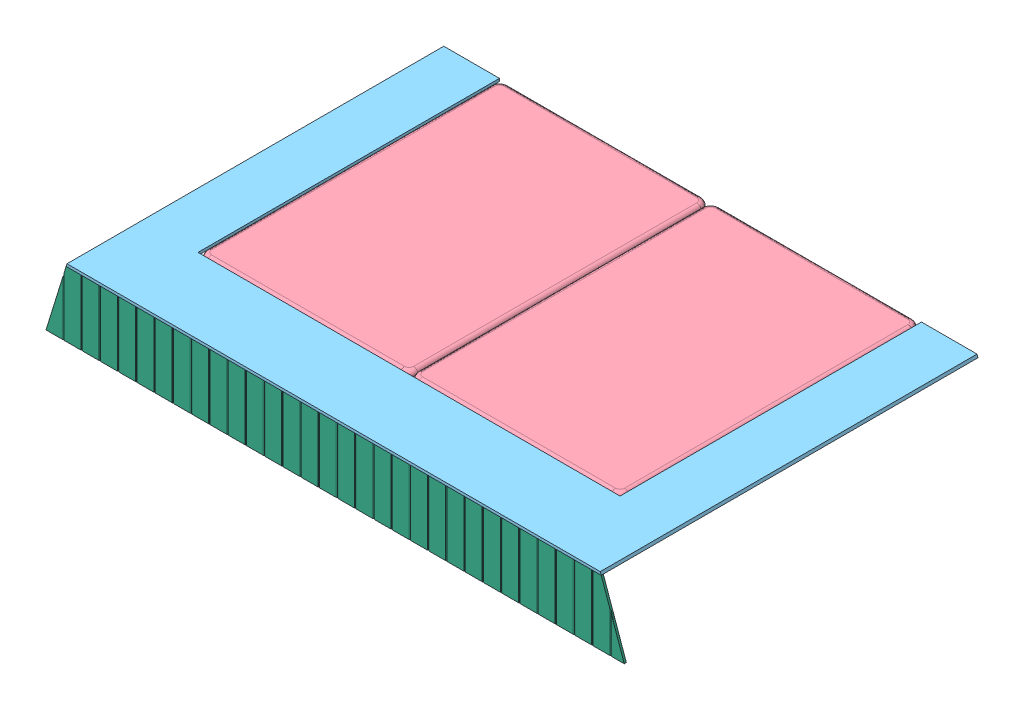
SolidWorks assembly Bett, configuration Standard. Lengths in mm.
Overall size (3836.71 450 2500).
155 component instances, 6 part files, 109 mates.
Components (placement in the parent):
- Lattenrost-1: Lattenrost [Standard] at (-502.8717 591.5866 942.3337) size (1400 86.11 2000)
  - Träger-1: Träger [Lang] at origin size (24 48 2000)
  - Träger-2: Träger [Lang] at (1376 0 0) size (24 48 2000)
  - Träger-3: Träger [Quer] at (1376 24 1960) x (0 1 0) z (-1 0 0) size (24 48 1352)
  - Träger-4: Träger [Quer] at (1376 24 88) x (0 1 0) z (-1 0 0) size (24 48 1352)
  - Gummi-Tüllen-1: Gummi-Tüllen [Standard] at (1365 54 1912.5) x (0 0 -1) z (1 0 0) size (117 12 35)
  - Gummi-Tüllen-2: Gummi-Tüllen [Standard] at (1365 54 1772.5) x (0 0 -1) z (1 0 0) size (117 12 35)
  - Gummi-Tüllen-3: Gummi-Tüllen [Standard] at (1365 54 1632.5) x (0 0 -1) z (1 0 0) size (117 12 35)
  - Gummi-Tüllen-4: Gummi-Tüllen [Standard] at (1365 54 1492.5) x (0 0 -1) z (1 0 0) size (117 12 35)
  - Gummi-Tüllen-5: Gummi-Tüllen [Standard] at (1365 54 1352.5) x (0 0 -1) z (1 0 0) size (117 12 35)
  - Gummi-Tüllen-6: Gummi-Tüllen [Standard] at (1365 54 1212.5) x (0 0 -1) z (1 0 0) size (117 12 35)
  - Gummi-Tüllen-7: Gummi-Tüllen [Standard] at (1365 54 1072.5) x (0 0 -1) z (1 0 0) size (117 12 35)
  - Gummi-Tüllen-8: Gummi-Tüllen [Standard] at (1365 54 932.5) x (0 0 -1) z (1 0 0) size (117 12 35)
  - Gummi-Tüllen-9: Gummi-Tüllen [Standard] at (1365 54 792.5) x (0 0 -1) z (1 0 0) size (117 12 35)
  - Gummi-Tüllen-10: Gummi-Tüllen [Standard] at (1365 54 652.5) x (0 0 -1) z (1 0 0) size (117 12 35)
  - Gummi-Tüllen-11: Gummi-Tüllen [Standard] at (1365 54 512.5) x (0 0 -1) z (1 0 0) size (117 12 35)
  - Gummi-Tüllen-12: Gummi-Tüllen [Standard] at (1365 54 372.5) x (0 0 -1) z (1 0 0) size (117 12 35)
  - Gummi-Tüllen-13: Gummi-Tüllen [Standard] at (1365 54 92.5) x (0 0 -1) z (1 0 0) size (117 12 35)
  - Gummi-Tüllen-14: Gummi-Tüllen [Standard] at (1365 54 232.5) x (0 0 -1) z (1 0 0) size (117 12 35)
  - Gummi-Tüllen-15: Gummi-Tüllen [Standard] at (35 54 1772.5) x (0 0 1) z (-1 0 0) size (117 12 35)
  - Gummi-Tüllen-16: Gummi-Tüllen [Standard] at (35 54 1912.5) x (0 0 1) z (-1 0 0) size (117 12 35)
  - Gummi-Tüllen-17: Gummi-Tüllen [Standard] at (35 54 1632.5) x (0 0 1) z (-1 0 0) size (117 12 35)
  - Gummi-Tüllen-18: Gummi-Tüllen [Standard] at (35 54 1492.5) x (0 0 1) z (-1 0 0) size (117 12 35)
  - Gummi-Tüllen-19: Gummi-Tüllen [Standard] at (35 54 1352.5) x (0 0 1) z (-1 0 0) size (117 12 35)
  - Gummi-Tüllen-20: Gummi-Tüllen [Standard] at (35 54 1212.5) x (0 0 1) z (-1 0 0) size (117 12 35)
  - Gummi-Tüllen-21: Gummi-Tüllen [Standard] at (35 54 1072.5) x (0 0 1) z (-1 0 0) size (117 12 35)
  - Gummi-Tüllen-22: Gummi-Tüllen [Standard] at (35 54 932.5) x (0 0 1) z (-1 0 0) size (117 12 35)
  - Gummi-Tüllen-23: Gummi-Tüllen [Standard] at (35 54 792.5) x (0 0 1) z (-1 0 0) size (117 12 35)
  - Gummi-Tüllen-24: Gummi-Tüllen [Standard] at (35 54 652.5) x (0 0 1) z (-1 0 0) size (117 12 35)
  - Gummi-Tüllen-25: Gummi-Tüllen [Standard] at (35 54 512.5) x (0 0 1) z (-1 0 0) size (117 12 35)
  - Gummi-Tüllen-26: Gummi-Tüllen [Standard] at (35 54 372.5) x (0 0 1) z (-1 0 0) size (117 12 35)
  - Gummi-Tüllen-27: Gummi-Tüllen [Standard] at (35 54 232.5) x (0 0 1) z (-1 0 0) size (117 12 35)
  - Gummi-Tüllen-28: Gummi-Tüllen [Standard] at (35 54 92.5) x (0 0 1) z (-1 0 0) size (117 12 35)
  - Latte-1: Latte [Einfach] at (700 46.1513 1930) size (1398 39.96 35)
  - Latte-2: Latte [Einfach] at (700 46.1513 1860) size (1398 39.96 35)
  - Latte-3: Latte [Einfach] at (700 46.1513 1790) size (1398 39.96 35)
  - Latte-4: Latte [Einfach] at (700 46.1513 1720) size (1398 39.96 35)
  - Latte-5: Latte [Einfach] at (700 46.1513 1650) size (1398 39.96 35)
  - Latte-6: Latte [Einfach] at (700 46.1513 1580) size (1398 39.96 35)
  - Latte-7: Latte [Einfach] at (700 46.1513 1510) size (1398 39.96 35)
  - Latte-8: Latte [Einfach] at (700 46.1513 1440) size (1398 39.96 35)
  - Latte-9: Latte [Einfach] at (700 46.1513 1370) size (1398 39.96 35)
  - Latte-10: Latte [Einfach] at (700 46.1513 1300) size (1398 39.96 35)
  - Latte-11: Latte [Einfach] at (700 46.1513 1230) size (1398 39.96 35)
  - Latte-12: Latte [Einfach] at (700 46.1513 1160) size (1398 39.96 35)
  - Latte-13: Latte [Einfach] at (700 46.1513 1090) size (1398 39.96 35)
  - Latte-14: Latte [Einfach] at (700 46.1513 1020) size (1398 39.96 35)
  - Latte-15: Latte [Einfach] at (700 46.1513 950) size (1398 39.96 35)
  - Latte-16: Latte [Einfach] at (700 46.1513 880) size (1398 39.96 35)
  - Latte-17: Latte [Einfach] at (700 46.1513 810) size (1398 39.96 35)
  - Latte-18: Latte [Einfach] at (700 46.1513 740) size (1398 39.96 35)
  - Latte-19: Latte [Einfach] at (700 46.1513 530) size (1398 39.96 35)
  - Latte-20: Latte [Einfach] at (700 46.1513 460) size (1398 39.96 35)
  - Latte-21: Latte [Einfach] at (700 46.1513 390) size (1398 39.96 35)
  - Latte-22: Latte [Einfach] at (700 46.1513 320) size (1398 39.96 35)
  - Latte-23: Latte [Einfach] at (700 46.1513 250) size (1398 39.96 35)
  - Latte-24: Latte [Einfach] at (700 46.1513 180) size (1398 39.96 35)
  - Latte-25: Latte [Einfach] at (700 46.1513 110) size (1398 39.96 35)
  - Latte-26: Latte [Einfach] at (700 46.1513 40) size (1398 39.96 35)
  - Latte-27: Latte [Doppel] at (700 46.1513 600) size (1398 39.96 105)
- Lattenrost-2: Lattenrost [Standard] at (897.1283 591.5866 942.3337) size (1400 86.11 2000)
  - Träger-1: Träger [Lang] at origin size (24 48 2000)
  - Träger-2: Träger [Lang] at (1376 0 0) size (24 48 2000)
  - Träger-3: Träger [Quer] at (1376 24 1960) x (0 1 0) z (-1 0 0) size (24 48 1352)
  - Träger-4: Träger [Quer] at (1376 24 88) x (0 1 0) z (-1 0 0) size (24 48 1352)
  - Gummi-Tüllen-1: Gummi-Tüllen [Standard] at (1365 54 1912.5) x (0 0 -1) z (1 0 0) size (117 12 35)
  - Gummi-Tüllen-2: Gummi-Tüllen [Standard] at (1365 54 1772.5) x (0 0 -1) z (1 0 0) size (117 12 35)
  - Gummi-Tüllen-3: Gummi-Tüllen [Standard] at (1365 54 1632.5) x (0 0 -1) z (1 0 0) size (117 12 35)
  - Gummi-Tüllen-4: Gummi-Tüllen [Standard] at (1365 54 1492.5) x (0 0 -1) z (1 0 0) size (117 12 35)
  - Gummi-Tüllen-5: Gummi-Tüllen [Standard] at (1365 54 1352.5) x (0 0 -1) z (1 0 0) size (117 12 35)
  - Gummi-Tüllen-6: Gummi-Tüllen [Standard] at (1365 54 1212.5) x (0 0 -1) z (1 0 0) size (117 12 35)
  - Gummi-Tüllen-7: Gummi-Tüllen [Standard] at (1365 54 1072.5) x (0 0 -1) z (1 0 0) size (117 12 35)
  - Gummi-Tüllen-8: Gummi-Tüllen [Standard] at (1365 54 932.5) x (0 0 -1) z (1 0 0) size (117 12 35)
  - Gummi-Tüllen-9: Gummi-Tüllen [Standard] at (1365 54 792.5) x (0 0 -1) z (1 0 0) size (117 12 35)
  - Gummi-Tüllen-10: Gummi-Tüllen [Standard] at (1365 54 652.5) x (0 0 -1) z (1 0 0) size (117 12 35)
  - Gummi-Tüllen-11: Gummi-Tüllen [Standard] at (1365 54 512.5) x (0 0 -1) z (1 0 0) size (117 12 35)
  - Gummi-Tüllen-12: Gummi-Tüllen [Standard] at (1365 54 372.5) x (0 0 -1) z (1 0 0) size (117 12 35)
  - Gummi-Tüllen-13: Gummi-Tüllen [Standard] at (1365 54 92.5) x (0 0 -1) z (1 0 0) size (117 12 35)
  - Gummi-Tüllen-14: Gummi-Tüllen [Standard] at (1365 54 232.5) x (0 0 -1) z (1 0 0) size (117 12 35)
  - Gummi-Tüllen-15: Gummi-Tüllen [Standard] at (35 54 1772.5) x (0 0 1) z (-1 0 0) size (117 12 35)
  - Gummi-Tüllen-16: Gummi-Tüllen [Standard] at (35 54 1912.5) x (0 0 1) z (-1 0 0) size (117 12 35)
  - Gummi-Tüllen-17: Gummi-Tüllen [Standard] at (35 54 1632.5) x (0 0 1) z (-1 0 0) size (117 12 35)
  - Gummi-Tüllen-18: Gummi-Tüllen [Standard] at (35 54 1492.5) x (0 0 1) z (-1 0 0) size (117 12 35)
  - Gummi-Tüllen-19: Gummi-Tüllen [Standard] at (35 54 1352.5) x (0 0 1) z (-1 0 0) size (117 12 35)
  - Gummi-Tüllen-20: Gummi-Tüllen [Standard] at (35 54 1212.5) x (0 0 1) z (-1 0 0) size (117 12 35)
  - Gummi-Tüllen-21: Gummi-Tüllen [Standard] at (35 54 1072.5) x (0 0 1) z (-1 0 0) size (117 12 35)
  - Gummi-Tüllen-22: Gummi-Tüllen [Standard] at (35 54 932.5) x (0 0 1) z (-1 0 0) size (117 12 35)
  - Gummi-Tüllen-23: Gummi-Tüllen [Standard] at (35 54 792.5) x (0 0 1) z (-1 0 0) size (117 12 35)
  - Gummi-Tüllen-24: Gummi-Tüllen [Standard] at (35 54 652.5) x (0 0 1) z (-1 0 0) size (117 12 35)
  - Gummi-Tüllen-25: Gummi-Tüllen [Standard] at (35 54 512.5) x (0 0 1) z (-1 0 0) size (117 12 35)
  - Gummi-Tüllen-26: Gummi-Tüllen [Standard] at (35 54 372.5) x (0 0 1) z (-1 0 0) size (117 12 35)
  - Gummi-Tüllen-27: Gummi-Tüllen [Standard] at (35 54 232.5) x (0 0 1) z (-1 0 0) size (117 12 35)
  - Gummi-Tüllen-28: Gummi-Tüllen [Standard] at (35 54 92.5) x (0 0 1) z (-1 0 0) size (117 12 35)
  - Latte-1: Latte [Einfach] at (700 46.1513 1930) size (1398 39.96 35)
  - Latte-2: Latte [Einfach] at (700 46.1513 1860) size (1398 39.96 35)
  - Latte-3: Latte [Einfach] at (700 46.1513 1790) size (1398 39.96 35)
  - Latte-4: Latte [Einfach] at (700 46.1513 1720) size (1398 39.96 35)
  - Latte-5: Latte [Einfach] at (700 46.1513 1650) size (1398 39.96 35)
  - Latte-6: Latte [Einfach] at (700 46.1513 1580) size (1398 39.96 35)
  - Latte-7: Latte [Einfach] at (700 46.1513 1510) size (1398 39.96 35)
  - Latte-8: Latte [Einfach] at (700 46.1513 1440) size (1398 39.96 35)
  - Latte-9: Latte [Einfach] at (700 46.1513 1370) size (1398 39.96 35)
  - Latte-10: Latte [Einfach] at (700 46.1513 1300) size (1398 39.96 35)
  - Latte-11: Latte [Einfach] at (700 46.1513 1230) size (1398 39.96 35)
  - Latte-12: Latte [Einfach] at (700 46.1513 1160) size (1398 39.96 35)
  - Latte-13: Latte [Einfach] at (700 46.1513 1090) size (1398 39.96 35)
  - Latte-14: Latte [Einfach] at (700 46.1513 1020) size (1398 39.96 35)
  - Latte-15: Latte [Einfach] at (700 46.1513 950) size (1398 39.96 35)
  - Latte-16: Latte [Einfach] at (700 46.1513 880) size (1398 39.96 35)
  - Latte-17: Latte [Einfach] at (700 46.1513 810) size (1398 39.96 35)
  - Latte-18: Latte [Einfach] at (700 46.1513 740) size (1398 39.96 35)
  - Latte-19: Latte [Einfach] at (700 46.1513 530) size (1398 39.96 35)
  - Latte-20: Latte [Einfach] at (700 46.1513 460) size (1398 39.96 35)
  - Latte-21: Latte [Einfach] at (700 46.1513 390) size (1398 39.96 35)
  - Latte-22: Latte [Einfach] at (700 46.1513 320) size (1398 39.96 35)
  - Latte-23: Latte [Einfach] at (700 46.1513 250) size (1398 39.96 35)
  - Latte-24: Latte [Einfach] at (700 46.1513 180) size (1398 39.96 35)
  - Latte-25: Latte [Einfach] at (700 46.1513 110) size (1398 39.96 35)
  - Latte-26: Latte [Einfach] at (700 46.1513 40) size (1398 39.96 35)
  - Latte-27: Latte [Doppel] at (700 46.1513 600) size (1398 39.96 105)
- Matratze-1: Matratze [140] at (197.1283 651.5866 1942.3337) size (1400 190 2000)
- Matratze-2: Matratze [140] at (1597.1283 651.5866 1942.3337) size (1400 190 2000)
- Platte-1: Platte [Standard] at (1968.2822 823.5866 1711.5645) size (3550 18 2500)
- Verkleidung-1: Verkleidung [Cut1-Left] at (-951.098 823.5866 3435.3337) x (1 0 0) z (0 0 -1) size (131 423.19 14)
- Verkleidung-2: Verkleidung [Cut2-Left] at (-830.098 823.5866 3435.3337) x (1 0 0) z (0 0 -1) size (131 432 14)
- Verkleidung-3: Verkleidung [Front] at (-709.098 823.5866 3435.3337) x (1 0 0) z (0 0 -1) size (131 432 14)
- Verkleidung-4: Verkleidung [Front] at (-588.098 823.5866 3435.3337) x (1 0 0) z (0 0 -1) size (131 432 14)
- Verkleidung-5: Verkleidung [Front] at (-467.098 823.5866 3435.3337) x (1 0 0) z (0 0 -1) size (131 432 14)
- Verkleidung-6: Verkleidung [Front] at (-346.098 823.5866 3435.3337) x (1 0 0) z (0 0 -1) size (131 432 14)
- Verkleidung-7: Verkleidung [Front] at (-225.098 823.5866 3435.3337) x (1 0 0) z (0 0 -1) size (131 432 14)
- Verkleidung-8: Verkleidung [Front] at (-104.098 823.5866 3435.3337) x (1 0 0) z (0 0 -1) size (131 432 14)
- Verkleidung-9: Verkleidung [Front] at (16.902 823.5866 3435.3337) x (1 0 0) z (0 0 -1) size (131 432 14)
- Verkleidung-10: Verkleidung [Front] at (137.902 823.5866 3435.3337) x (1 0 0) z (0 0 -1) size (131 432 14)
- Verkleidung-11: Verkleidung [Front] at (258.902 823.5866 3435.3337) x (1 0 0) z (0 0 -1) size (131 432 14)
- Verkleidung-12: Verkleidung [Front] at (379.902 823.5866 3435.3337) x (1 0 0) z (0 0 -1) size (131 432 14)
- Verkleidung-13: Verkleidung [Front] at (500.902 823.5866 3435.3337) x (1 0 0) z (0 0 -1) size (131 432 14)
- Verkleidung-14: Verkleidung [Front] at (621.902 823.5866 3435.3337) x (1 0 0) z (0 0 -1) size (131 432 14)
- Verkleidung-15: Verkleidung [Front] at (742.902 823.5866 3435.3337) x (1 0 0) z (0 0 -1) size (131 432 14)
- Verkleidung-16: Verkleidung [Front] at (863.902 823.5866 3435.3337) x (1 0 0) z (0 0 -1) size (131 432 14)
- Verkleidung-17: Verkleidung [Front] at (984.902 823.5866 3435.3337) x (1 0 0) z (0 0 -1) size (131 432 14)
- Verkleidung-18: Verkleidung [Front] at (1105.902 823.5866 3435.3337) x (1 0 0) z (0 0 -1) size (131 432 14)
- Verkleidung-19: Verkleidung [Front] at (1226.902 823.5866 3435.3337) x (1 0 0) z (0 0 -1) size (131 432 14)
- Verkleidung-20: Verkleidung [Front] at (1347.902 823.5866 3435.3337) x (1 0 0) z (0 0 -1) size (131 432 14)
- Verkleidung-21: Verkleidung [Front] at (1468.902 823.5866 3435.3337) x (1 0 0) z (0 0 -1) size (131 432 14)
- Verkleidung-22: Verkleidung [Front] at (1589.902 823.5866 3435.3337) x (1 0 0) z (0 0 -1) size (131 432 14)
- Verkleidung-23: Verkleidung [Front] at (1710.902 823.5866 3435.3337) x (1 0 0) z (0 0 -1) size (131 432 14)
- Verkleidung-24: Verkleidung [Front] at (1831.902 823.5866 3435.3337) x (1 0 0) z (0 0 -1) size (131 432 14)
- Verkleidung-25: Verkleidung [Front] at (1952.902 823.5866 3435.3337) x (1 0 0) z (0 0 -1) size (131 432 14)
- Verkleidung-26: Verkleidung [Front] at (2073.902 823.5866 3435.3337) x (1 0 0) z (0 0 -1) size (131 432 14)
- Verkleidung-27: Verkleidung [Front] at (2194.902 823.5866 3435.3337) x (1 0 0) z (0 0 -1) size (131 432 14)
- Verkleidung-28: Verkleidung [Front] at (2315.902 823.5866 3435.3337) x (1 0 0) z (0 0 -1) size (131 432 14)
- Verkleidung-29: Verkleidung [Front] at (2436.902 823.5866 3435.3337) x (1 0 0) z (0 0 -1) size (131 432 14)
- Verkleidung-32: Verkleidung [Front] at (2557.902 823.5866 3435.3337) x (1 0 0) z (0 0 -1) size (131 432 14)
- Verkleidung-33: Verkleidung [Cut1-Right] at (2678.902 823.5866 3435.3337) x (1 0 0) z (0 0 -1) size (131 432 14)
- Verkleidung-34: Verkleidung [Cut2-Right] at (2799.902 823.5866 3435.3337) x (1 0 0) z (0 0 -1) size (85.71 242.03 14)
Mates (geometry in assembly coordinates):
- Deckungsgleich1: coincident aligned: plane of Lattenrost-1/Träger-2 through (873.1283 591.5866 2942.3337) normal (0 -1 0); plane of Lattenrost-2/Träger-1 through (897.1283 591.5866 2942.3337) normal (0 -1 0)
- Deckungsgleich2: coincident aligned: plane of Lattenrost-1/Träger-2 through (873.1283 591.5866 2942.3337) normal (0 0 1); plane of Lattenrost-2/Träger-1 through (897.1283 591.5866 2942.3337) normal (0 0 1)
- Deckungsgleich3: coincident anti-aligned: plane of Lattenrost-1/Träger-2 through (897.1283 591.5866 2942.3337) normal (1 0 0); plane of Lattenrost-2/Träger-1 through (897.1283 591.5866 2942.3337) normal (-1 0 0)
- Deckungsgleich4: coincident anti-aligned: plane of Lattenrost-1/Gummi-Tüllen-1 through (886.1283 651.5866 2872.3337) normal (0 1 0); plane of Matratze-1 through (197.1283 651.5866 1942.3337) normal (0 -1 0)
- Deckungsgleich5: coincident: line of Lattenrost-1/Träger-2 through (897.1283 591.5866 2942.3337) axis (0 1 0); plane of Matratze-1 through (897.1283 841.5866 2942.3337) normal (1 0 0)
- Deckungsgleich6: coincident aligned: plane of Lattenrost-1/Träger-2 through (873.1283 591.5866 2942.3337) normal (0 0 1); plane of Matratze-1 through (-502.8717 841.5866 2942.3337) normal (0 0 1)
- Deckungsgleich7: coincident anti-aligned: plane of Matratze-1 through (897.1283 841.5866 2942.3337) normal (1 0 0); plane of Matratze-2 through (897.1283 841.5866 2942.3337) normal (-1 0 0)
- Deckungsgleich8: coincident aligned: plane of Matratze-1 through (-502.8717 841.5866 2942.3337) normal (0 0 1); plane of Matratze-2 through (897.1283 841.5866 2942.3337) normal (0 0 1)
- Deckungsgleich9: coincident aligned: plane of Matratze-1 through (197.1283 841.5866 1942.3337) normal (0 1 0); plane of Matratze-2 through (1597.1283 841.5866 1942.3337) normal (0 1 0)
- Deckungsgleich10: coincident aligned: plane of Matratze-1 through (197.1283 841.5866 1942.3337) normal (0 1 0); plane of Platte-1 through (1968.2822 841.5866 1711.5645) normal (0 1 0)
- Deckungsgleich11: coincident anti-aligned: plane of Matratze-1 through (-502.8717 841.5866 2942.3337) normal (0 0 1); plane of Platte-1 through (-502.8717 841.5866 2942.3337) normal (0 0 -1)
- Deckungsgleich12: coincident anti-aligned: plane of Matratze-1 through (-502.8717 841.5866 2942.3337) normal (-1 0 0); plane of Platte-1 through (-502.8717 841.5866 942.3337) normal (1 0 0)
- Deckungsgleich16: coincident aligned: plane of Verkleidung-1 through (-890.598 391.5866 3428.3337) normal (0 0 -1); plane of Verkleidung-2 through (-769.598 391.5866 3428.3337) normal (0 0 -1)
- Deckungsgleich17: coincident anti-aligned: plane of Verkleidung-1 through (-880.598 391.5866 3433.3337) normal (0 0 -1); plane of Verkleidung-2 through (-890.598 391.5866 3433.3337) normal (0 0 1)
- Deckungsgleich18: coincident anti-aligned: plane of Verkleidung-1 through (-880.598 391.5866 3437.3337) normal (1 0 0); plane of Verkleidung-2 through (-880.598 391.5866 3433.3337) normal (-1 0 0)
- Deckungsgleich37: coincident anti-aligned: plane of Verkleidung-2 through (-759.598 391.5866 3433.3337) normal (0 0 -1); plane of Verkleidung-3 through (-769.598 391.5866 3433.3337) normal (0 0 1)
- Deckungsgleich38: coincident anti-aligned: plane of Verkleidung-3 through (-638.598 391.5866 3433.3337) normal (0 0 -1); plane of Verkleidung-4 through (-648.598 391.5866 3433.3337) normal (0 0 1)
- Deckungsgleich39: coincident anti-aligned: plane of Verkleidung-4 through (-517.598 391.5866 3433.3337) normal (0 0 -1); plane of Verkleidung-5 through (-527.598 391.5866 3433.3337) normal (0 0 1)
- Deckungsgleich40: coincident anti-aligned: plane of Verkleidung-5 through (-396.598 391.5866 3433.3337) normal (0 0 -1); plane of Verkleidung-6 through (-406.598 391.5866 3433.3337) normal (0 0 1)
- Deckungsgleich41: coincident anti-aligned: plane of Verkleidung-6 through (-275.598 391.5866 3433.3337) normal (0 0 -1); plane of Verkleidung-7 through (-285.598 391.5866 3433.3337) normal (0 0 1)
- Deckungsgleich42: coincident anti-aligned: plane of Verkleidung-7 through (-154.598 391.5866 3433.3337) normal (0 0 -1); plane of Verkleidung-8 through (-164.598 391.5866 3433.3337) normal (0 0 1)
- Deckungsgleich43: coincident anti-aligned: plane of Verkleidung-8 through (-33.598 391.5866 3433.3337) normal (0 0 -1); plane of Verkleidung-9 through (-43.598 391.5866 3433.3337) normal (0 0 1)
- Deckungsgleich44: coincident anti-aligned: plane of Verkleidung-9 through (87.402 391.5866 3433.3337) normal (0 0 -1); plane of Verkleidung-10 through (77.402 391.5866 3433.3337) normal (0 0 1)
- Deckungsgleich45: coincident anti-aligned: plane of Verkleidung-10 through (208.402 391.5866 3433.3337) normal (0 0 -1); plane of Verkleidung-11 through (198.402 391.5866 3433.3337) normal (0 0 1)
- Deckungsgleich46: coincident anti-aligned: plane of Verkleidung-11 through (329.402 391.5866 3433.3337) normal (0 0 -1); plane of Verkleidung-12 through (319.402 391.5866 3433.3337) normal (0 0 1)
- Deckungsgleich47: coincident anti-aligned: plane of Verkleidung-12 through (450.402 391.5866 3433.3337) normal (0 0 -1); plane of Verkleidung-13 through (440.402 391.5866 3433.3337) normal (0 0 1)
- Deckungsgleich48: coincident anti-aligned: plane of Verkleidung-13 through (571.402 391.5866 3433.3337) normal (0 0 -1); plane of Verkleidung-14 through (561.402 391.5866 3433.3337) normal (0 0 1)
- Deckungsgleich49: coincident anti-aligned: plane of Verkleidung-14 through (692.402 391.5866 3433.3337) normal (0 0 -1); plane of Verkleidung-15 through (682.402 391.5866 3433.3337) normal (0 0 1)
- Deckungsgleich50: coincident anti-aligned: plane of Verkleidung-15 through (813.402 391.5866 3433.3337) normal (0 0 -1); plane of Verkleidung-16 through (803.402 391.5866 3433.3337) normal (0 0 1)
- Deckungsgleich51: coincident anti-aligned: plane of Verkleidung-16 through (934.402 391.5866 3433.3337) normal (0 0 -1); plane of Verkleidung-17 through (924.402 391.5866 3433.3337) normal (0 0 1)
- Deckungsgleich52: coincident anti-aligned: plane of Verkleidung-17 through (1055.402 391.5866 3433.3337) normal (0 0 -1); plane of Verkleidung-18 through (1045.402 391.5866 3433.3337) normal (0 0 1)
- Deckungsgleich65: coincident anti-aligned: plane of Verkleidung-18 through (1176.402 391.5866 3433.3337) normal (0 0 -1); plane of Verkleidung-19 through (1166.402 391.5866 3433.3337) normal (0 0 1)
- Deckungsgleich66: coincident anti-aligned: plane of Verkleidung-19 through (1297.402 391.5866 3433.3337) normal (0 0 -1); plane of Verkleidung-20 through (1287.402 391.5866 3433.3337) normal (0 0 1)
- Deckungsgleich67: coincident anti-aligned: plane of Verkleidung-20 through (1418.402 391.5866 3433.3337) normal (0 0 -1); plane of Verkleidung-21 through (1408.402 391.5866 3433.3337) normal (0 0 1)
- Deckungsgleich68: coincident anti-aligned: plane of Verkleidung-21 through (1539.402 391.5866 3433.3337) normal (0 0 -1); plane of Verkleidung-22 through (1529.402 391.5866 3433.3337) normal (0 0 1)
- Deckungsgleich69: coincident anti-aligned: plane of Verkleidung-22 through (1660.402 391.5866 3433.3337) normal (0 0 -1); plane of Verkleidung-23 through (1650.402 391.5866 3433.3337) normal (0 0 1)
- Deckungsgleich70: coincident anti-aligned: plane of Verkleidung-23 through (1781.402 391.5866 3433.3337) normal (0 0 -1); plane of Verkleidung-24 through (1771.402 391.5866 3433.3337) normal (0 0 1)
- Deckungsgleich71: coincident anti-aligned: plane of Verkleidung-24 through (1902.402 391.5866 3433.3337) normal (0 0 -1); plane of Verkleidung-25 through (1892.402 391.5866 3433.3337) normal (0 0 1)
- Deckungsgleich72: coincident anti-aligned: plane of Verkleidung-25 through (2023.402 391.5866 3433.3337) normal (0 0 -1); plane of Verkleidung-26 through (2013.402 391.5866 3433.3337) normal (0 0 1)
- Deckungsgleich73: coincident anti-aligned: plane of Verkleidung-26 through (2144.402 391.5866 3433.3337) normal (0 0 -1); plane of Verkleidung-27 through (2134.402 391.5866 3433.3337) normal (0 0 1)
- Deckungsgleich74: coincident anti-aligned: plane of Verkleidung-27 through (2265.402 391.5866 3433.3337) normal (0 0 -1); plane of Verkleidung-28 through (2255.402 391.5866 3433.3337) normal (0 0 1)
- Deckungsgleich75: coincident anti-aligned: plane of Verkleidung-28 through (2386.402 391.5866 3433.3337) normal (0 0 -1); plane of Verkleidung-29 through (2376.402 391.5866 3433.3337) normal (0 0 1)
- Deckungsgleich76: coincident anti-aligned: plane of Verkleidung-2 through (-759.598 391.5866 3437.3337) normal (1 0 0); plane of Verkleidung-3 through (-759.598 391.5866 3433.3337) normal (-1 0 0)
- Deckungsgleich77: coincident anti-aligned: plane of Verkleidung-3 through (-638.598 391.5866 3437.3337) normal (1 0 0); plane of Verkleidung-4 through (-638.598 391.5866 3433.3337) normal (-1 0 0)
- Deckungsgleich78: coincident anti-aligned: plane of Verkleidung-4 through (-517.598 391.5866 3437.3337) normal (1 0 0); plane of Verkleidung-5 through (-517.598 391.5866 3433.3337) normal (-1 0 0)
- Deckungsgleich79: coincident anti-aligned: plane of Verkleidung-5 through (-396.598 391.5866 3437.3337) normal (1 0 0); plane of Verkleidung-6 through (-396.598 391.5866 3433.3337) normal (-1 0 0)
- Deckungsgleich80: coincident anti-aligned: plane of Verkleidung-6 through (-275.598 391.5866 3437.3337) normal (1 0 0); plane of Verkleidung-7 through (-275.598 391.5866 3433.3337) normal (-1 0 0)
- Deckungsgleich81: coincident anti-aligned: plane of Verkleidung-7 through (-154.598 391.5866 3437.3337) normal (1 0 0); plane of Verkleidung-8 through (-154.598 391.5866 3433.3337) normal (-1 0 0)
- Deckungsgleich82: coincident anti-aligned: plane of Verkleidung-8 through (-33.598 391.5866 3437.3337) normal (1 0 0); plane of Verkleidung-9 through (-33.598 391.5866 3433.3337) normal (-1 0 0)
- Deckungsgleich83: coincident anti-aligned: plane of Verkleidung-9 through (87.402 391.5866 3437.3337) normal (1 0 0); plane of Verkleidung-10 through (87.402 391.5866 3433.3337) normal (-1 0 0)
- Deckungsgleich84: coincident anti-aligned: plane of Verkleidung-10 through (208.402 391.5866 3437.3337) normal (1 0 0); plane of Verkleidung-11 through (208.402 391.5866 3433.3337) normal (-1 0 0)
- Deckungsgleich85: coincident anti-aligned: plane of Verkleidung-11 through (329.402 391.5866 3437.3337) normal (1 0 0); plane of Verkleidung-12 through (329.402 391.5866 3433.3337) normal (-1 0 0)
- Deckungsgleich86: coincident anti-aligned: plane of Verkleidung-12 through (450.402 391.5866 3437.3337) normal (1 0 0); plane of Verkleidung-13 through (450.402 391.5866 3433.3337) normal (-1 0 0)
- Deckungsgleich87: coincident anti-aligned: plane of Verkleidung-13 through (571.402 391.5866 3437.3337) normal (1 0 0); plane of Verkleidung-14 through (571.402 391.5866 3433.3337) normal (-1 0 0)
- Deckungsgleich88: coincident anti-aligned: plane of Verkleidung-14 through (692.402 391.5866 3437.3337) normal (1 0 0); plane of Verkleidung-15 through (692.402 391.5866 3433.3337) normal (-1 0 0)
- Deckungsgleich89: coincident anti-aligned: plane of Verkleidung-15 through (813.402 391.5866 3437.3337) normal (1 0 0); plane of Verkleidung-16 through (813.402 391.5866 3433.3337) normal (-1 0 0)
- Deckungsgleich90: coincident anti-aligned: plane of Verkleidung-16 through (934.402 391.5866 3437.3337) normal (1 0 0); plane of Verkleidung-17 through (934.402 391.5866 3433.3337) normal (-1 0 0)
- Deckungsgleich93: coincident anti-aligned: plane of Verkleidung-17 through (1055.402 391.5866 3437.3337) normal (1 0 0); plane of Verkleidung-18 through (1055.402 391.5866 3433.3337) normal (-1 0 0)
- Deckungsgleich94: coincident anti-aligned: plane of Verkleidung-18 through (1176.402 391.5866 3437.3337) normal (1 0 0); plane of Verkleidung-19 through (1176.402 391.5866 3433.3337) normal (-1 0 0)
- Deckungsgleich95: coincident anti-aligned: plane of Verkleidung-19 through (1297.402 391.5866 3437.3337) normal (1 0 0); plane of Verkleidung-20 through (1297.402 391.5866 3433.3337) normal (-1 0 0)
- Deckungsgleich97: coincident anti-aligned: plane of Verkleidung-20 through (1418.402 391.5866 3437.3337) normal (1 0 0); plane of Verkleidung-21 through (1418.402 391.5866 3433.3337) normal (-1 0 0)
- Deckungsgleich98: coincident anti-aligned: plane of Verkleidung-21 through (1539.402 391.5866 3437.3337) normal (1 0 0); plane of Verkleidung-22 through (1539.402 391.5866 3433.3337) normal (-1 0 0)
- Deckungsgleich99: coincident anti-aligned: plane of Verkleidung-22 through (1660.402 391.5866 3437.3337) normal (1 0 0); plane of Verkleidung-23 through (1660.402 391.5866 3433.3337) normal (-1 0 0)
- Deckungsgleich100: coincident anti-aligned: plane of Verkleidung-23 through (1781.402 391.5866 3437.3337) normal (1 0 0); plane of Verkleidung-24 through (1781.402 391.5866 3433.3337) normal (-1 0 0)
- Deckungsgleich101: coincident anti-aligned: plane of Verkleidung-24 through (1902.402 391.5866 3437.3337) normal (1 0 0); plane of Verkleidung-25 through (1902.402 391.5866 3433.3337) normal (-1 0 0)
- Deckungsgleich102: coincident anti-aligned: plane of Verkleidung-25 through (2023.402 391.5866 3437.3337) normal (1 0 0); plane of Verkleidung-26 through (2023.402 391.5866 3433.3337) normal (-1 0 0)
- Deckungsgleich103: coincident anti-aligned: plane of Verkleidung-26 through (2144.402 391.5866 3437.3337) normal (1 0 0); plane of Verkleidung-27 through (2144.402 391.5866 3433.3337) normal (-1 0 0)
- Deckungsgleich104: coincident anti-aligned: plane of Verkleidung-27 through (2265.402 391.5866 3437.3337) normal (1 0 0); plane of Verkleidung-28 through (2265.402 391.5866 3433.3337) normal (-1 0 0)
- Deckungsgleich105: coincident anti-aligned: plane of Verkleidung-28 through (2386.402 391.5866 3437.3337) normal (1 0 0); plane of Verkleidung-29 through (2386.402 391.5866 3433.3337) normal (-1 0 0)
- Deckungsgleich106: coincident aligned: plane of Verkleidung-2 through (-780.598 823.5866 3438.3337) normal (0 1 0); plane of Verkleidung-3 through (-659.598 823.5866 3438.3337) normal (0 1 0)
- Deckungsgleich107: coincident aligned: plane of Verkleidung-3 through (-659.598 823.5866 3438.3337) normal (0 1 0); plane of Verkleidung-4 through (-538.598 823.5866 3438.3337) normal (0 1 0)
- Deckungsgleich108: coincident aligned: plane of Verkleidung-4 through (-538.598 823.5866 3438.3337) normal (0 1 0); plane of Verkleidung-5 through (-417.598 823.5866 3438.3337) normal (0 1 0)
- Deckungsgleich109: coincident aligned: plane of Verkleidung-5 through (-417.598 823.5866 3438.3337) normal (0 1 0); plane of Verkleidung-6 through (-296.598 823.5866 3438.3337) normal (0 1 0)
- Deckungsgleich110: coincident aligned: plane of Verkleidung-6 through (-296.598 823.5866 3438.3337) normal (0 1 0); plane of Verkleidung-7 through (-175.598 823.5866 3438.3337) normal (0 1 0)
- Deckungsgleich111: coincident aligned: plane of Verkleidung-7 through (-175.598 823.5866 3438.3337) normal (0 1 0); plane of Verkleidung-8 through (-54.598 823.5866 3438.3337) normal (0 1 0)
- Deckungsgleich112: coincident aligned: plane of Verkleidung-8 through (-54.598 823.5866 3438.3337) normal (0 1 0); plane of Verkleidung-9 through (66.402 823.5866 3438.3337) normal (0 1 0)
- Deckungsgleich113: coincident aligned: plane of Verkleidung-9 through (66.402 823.5866 3438.3337) normal (0 1 0); plane of Verkleidung-10 through (187.402 823.5866 3438.3337) normal (0 1 0)
- Deckungsgleich114: coincident aligned: plane of Verkleidung-10 through (187.402 823.5866 3438.3337) normal (0 1 0); plane of Verkleidung-11 through (308.402 823.5866 3438.3337) normal (0 1 0)
- Deckungsgleich115: coincident aligned: plane of Verkleidung-11 through (308.402 823.5866 3438.3337) normal (0 1 0); plane of Verkleidung-12 through (429.402 823.5866 3438.3337) normal (0 1 0)
- Deckungsgleich116: coincident aligned: plane of Verkleidung-12 through (429.402 823.5866 3438.3337) normal (0 1 0); plane of Verkleidung-13 through (550.402 823.5866 3438.3337) normal (0 1 0)
- Deckungsgleich117: coincident aligned: plane of Verkleidung-13 through (550.402 823.5866 3438.3337) normal (0 1 0); plane of Verkleidung-14 through (671.402 823.5866 3438.3337) normal (0 1 0)
- Deckungsgleich118: coincident aligned: plane of Verkleidung-14 through (671.402 823.5866 3438.3337) normal (0 1 0); plane of Verkleidung-15 through (792.402 823.5866 3438.3337) normal (0 1 0)
- Deckungsgleich119: coincident aligned: plane of Verkleidung-15 through (792.402 823.5866 3438.3337) normal (0 1 0); plane of Verkleidung-16 through (913.402 823.5866 3438.3337) normal (0 1 0)
- Deckungsgleich120: coincident aligned: plane of Verkleidung-16 through (913.402 823.5866 3438.3337) normal (0 1 0); plane of Verkleidung-17 through (1034.402 823.5866 3438.3337) normal (0 1 0)
- Deckungsgleich121: coincident aligned: plane of Verkleidung-17 through (1034.402 823.5866 3438.3337) normal (0 1 0); plane of Verkleidung-18 through (1155.402 823.5866 3438.3337) normal (0 1 0)
- Deckungsgleich122: coincident aligned: plane of Verkleidung-18 through (1155.402 823.5866 3438.3337) normal (0 1 0); plane of Verkleidung-19 through (1276.402 823.5866 3438.3337) normal (0 1 0)
- Deckungsgleich123: coincident aligned: plane of Verkleidung-19 through (1276.402 823.5866 3438.3337) normal (0 1 0); plane of Verkleidung-20 through (1397.402 823.5866 3438.3337) normal (0 1 0)
- Deckungsgleich124: coincident aligned: plane of Verkleidung-20 through (1397.402 823.5866 3438.3337) normal (0 1 0); plane of Verkleidung-21 through (1518.402 823.5866 3438.3337) normal (0 1 0)
- Deckungsgleich125: coincident aligned: plane of Verkleidung-21 through (1518.402 823.5866 3438.3337) normal (0 1 0); plane of Verkleidung-22 through (1639.402 823.5866 3438.3337) normal (0 1 0)
- Deckungsgleich126: coincident aligned: plane of Verkleidung-22 through (1639.402 823.5866 3438.3337) normal (0 1 0); plane of Verkleidung-23 through (1760.402 823.5866 3438.3337) normal (0 1 0)
- Deckungsgleich127: coincident aligned: plane of Verkleidung-23 through (1760.402 823.5866 3438.3337) normal (0 1 0); plane of Verkleidung-24 through (1881.402 823.5866 3438.3337) normal (0 1 0)
- Deckungsgleich128: coincident aligned: plane of Verkleidung-24 through (1881.402 823.5866 3438.3337) normal (0 1 0); plane of Verkleidung-25 through (2002.402 823.5866 3438.3337) normal (0 1 0)
- Deckungsgleich129: coincident aligned: plane of Verkleidung-25 through (2002.402 823.5866 3438.3337) normal (0 1 0); plane of Verkleidung-26 through (2123.402 823.5866 3438.3337) normal (0 1 0)
- Deckungsgleich130: coincident aligned: plane of Verkleidung-26 through (2123.402 823.5866 3438.3337) normal (0 1 0); plane of Verkleidung-27 through (2244.402 823.5866 3438.3337) normal (0 1 0)
- Deckungsgleich131: coincident aligned: plane of Verkleidung-27 through (2244.402 823.5866 3438.3337) normal (0 1 0); plane of Verkleidung-28 through (2365.402 823.5866 3438.3337) normal (0 1 0)
- Deckungsgleich132: coincident aligned: plane of Verkleidung-28 through (2365.402 823.5866 3438.3337) normal (0 1 0); plane of Verkleidung-29 through (2486.402 823.5866 3438.3337) normal (0 1 0)
- Deckungsgleich134: coincident anti-aligned: plane of Platte-1 through (1968.2822 823.5866 1711.5645) normal (0 -1 0); plane of Verkleidung-2 through (-780.598 823.5866 3438.3337) normal (0 1 0)
- Deckungsgleich135: coincident aligned: plane of Platte-1 through (2672.1283 841.5866 3442.3337) normal (0 0 1); plane of Verkleidung-1 through (-901.598 391.5866 3442.3337) normal (0 0 1)
- Deckungsgleich136: coincident aligned: plane of Verkleidung-1 through (-901.598 391.5866 3438.3337) normal (0 -1 0); plane of Verkleidung-2 through (-780.598 391.5866 3438.3337) normal (0 -1 0)
- Deckungsgleich137: coincident aligned: plane of Platte-1 through (-877.8717 823.5866 442.3337) normal (-0.955278 0.295708 0); plane of Verkleidung-1 through (-877.8717 823.5866 3458.3337) normal (-0.955278 0.295708 0)
- Deckungsgleich142: coincident aligned: plane of Verkleidung-29 through (2486.402 391.5866 3438.3337) normal (0 -1 0); plane of Verkleidung-32 through (2607.402 391.5866 3438.3337) normal (0 -1 0)
- Deckungsgleich143: coincident aligned: plane of Verkleidung-32 through (2607.402 391.5866 3438.3337) normal (0 -1 0); plane of Verkleidung-33 through (2728.402 391.5866 3438.3337) normal (0 -1 0)
- Deckungsgleich144: coincident anti-aligned: plane of Verkleidung-29 through (2497.402 391.5866 3437.3337) normal (0 0 1); plane of Verkleidung-32 through (2507.402 391.5866 3437.3337) normal (0 0 -1)
- Deckungsgleich145: coincident anti-aligned: plane of Verkleidung-32 through (2618.402 391.5866 3437.3337) normal (0 0 1); plane of Verkleidung-33 through (2628.402 391.5866 3437.3337) normal (0 0 -1)
- Deckungsgleich146: coincident anti-aligned: plane of Verkleidung-29 through (2507.402 391.5866 3437.3337) normal (1 0 0); plane of Verkleidung-32 through (2507.402 391.5866 3433.3337) normal (-1 0 0)
- Deckungsgleich147: coincident anti-aligned: plane of Verkleidung-32 through (2628.402 391.5866 3437.3337) normal (1 0 0); plane of Verkleidung-33 through (2628.402 391.5866 3433.3337) normal (-1 0 0)
- Deckungsgleich148: coincident aligned: plane of Verkleidung-33 through (2728.402 391.5866 3438.3337) normal (0 -1 0); plane of Verkleidung-34 through (2849.402 391.5866 3438.3337) normal (0 -1 0)
- Deckungsgleich149: coincident anti-aligned: plane of Verkleidung-33 through (2739.402 391.5866 3437.3337) normal (0 0 1); plane of Verkleidung-34 through (2749.402 391.5866 3437.3337) normal (0 0 -1)
- Deckungsgleich150: coincident anti-aligned: plane of Verkleidung-33 through (2749.402 391.5866 3437.3337) normal (1 0 0); plane of Verkleidung-34 through (2749.402 391.5866 3433.3337) normal (-1 0 0)
